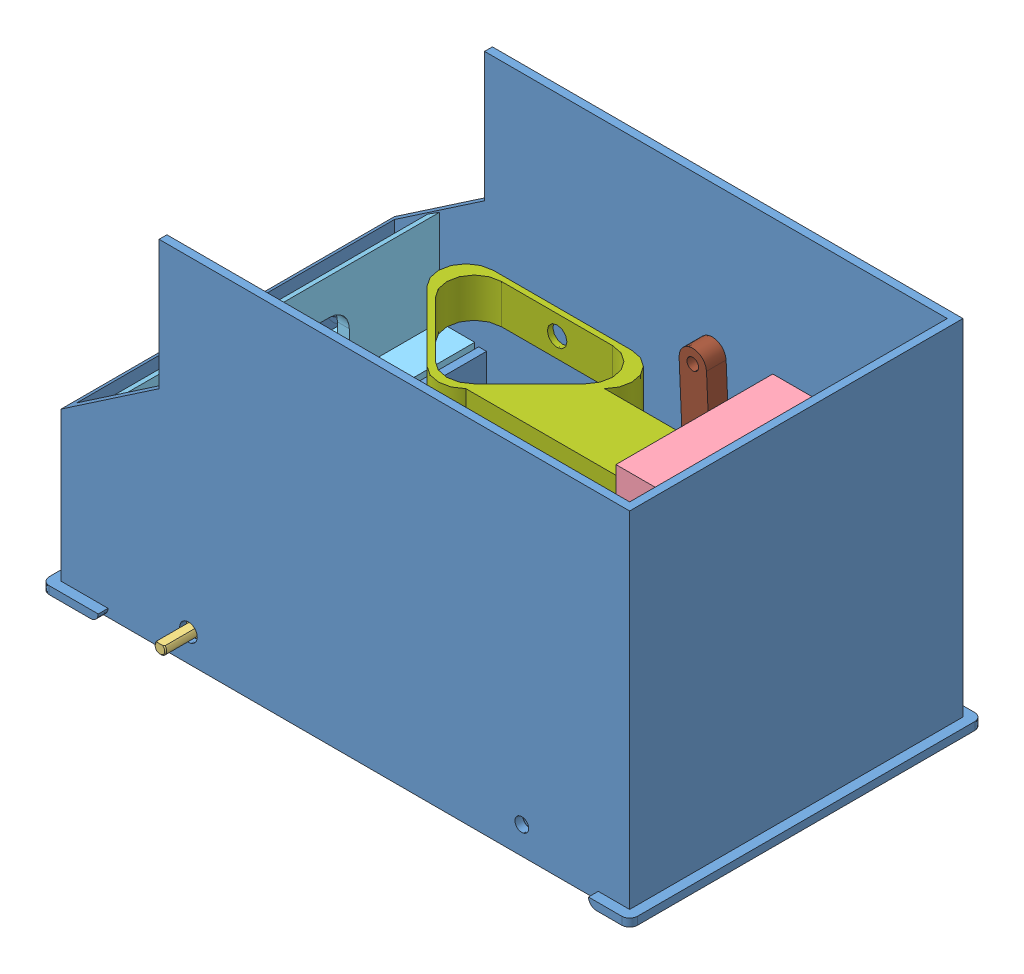
SolidWorks assembly Assemblage Robot, configuration Défaut. Lengths in mm.
Overall size (150 90 99.54).
20 component instances, 16 part files, 31 mates.
Components (placement in the parent):
- Assemblage_chassis-1: Assemblage_chassis [Défaut] at (-33.7926 -26.5183 11.2565) size (150 90 90)
  - chassis-1: chassis [Défaut] at (-70.5411 -39.149 105) size (150 90 90)
  - suppport arduino-1: suppport arduino [Défaut] at (13.9589 3.985 192.5) x (-1 0 0) z (0 -1 0) size (72 6 60)
- coque-1: coque [Défaut] at (-104.3337 -67.6673 194.8478) x (-1 0 0) z (0 0 -1) size (150 91.58 90) (hidden)
- Micro Moto Réducteur-2: Micro Moto Réducteur [Default] at (-69.3337 -60.6673 185.2565) size (12 10 35.27)
- Micro Moto Réducteur-3: Micro Moto Réducteur [Default] at (-69.3337 -60.6673 137.2565) x (-1 0 0) z (0 0 -1) size (12 10 35.27)
- Batterie-2: Batterie [Défaut] at (41.1663 10.3327 143.2565) x (0 1 0) z (0 0 1) size (76 22 40)
- Pièce1^Assemblage Robot-1: Pièce1^Assemblage Robot [Défaut] at origin (virtual)
- picèce led-1: picèce led [Défaut] at (-99.8337 -44.6673 201.2565) x (-1 0 0) z (0 0 -1) size (21 47.2 80)
- maintien-1: maintien [Défaut] at (5.3663 -65.6673 163.6265) x (-1 0 0) z (0 0 1) size (12 54.01 10)
- maintien-2: maintien [Défaut] at (5.3663 -65.6673 135.6565) x (-1 0 0) z (0 0 1) size (12 54.01 10)
- chassis terminer^Assemblage Robot-1: chassis terminer^Assemblage Robot [Défaut<Brut d'usinage>] at origin (virtual)
- support crayon-1: support crayon [Défaut] at (-43.6715 -21.6673 168.5763) x (-1 0 0) z (0 0 -1) size (83.19 10 31.68)
- goupille 6mm-1: goupille 6mm [Défaut] at (11.3663 -16.6673 153.6265) x (-0.72136 0.69256 0) z (0 0 1) size (6 6 40)
- servomoteur-1: servomoteur [Défaut] at (-1.4391 -65.6573 161.7565) x (0 1 0) z (-1 0 0) size (20 27 9)
- piece pignon servomoteur-1: piece pignon servomoteur [Default] at (-5.9391 -60.6573 135.7565) x (0.009859 0.999951 0) z (0 0 1) size (14.81 6 5)
- tige piece servomoteur-1: tige piece servomoteur [Default] at (-6.6703 -50.7455 130.7565) x (0.045193 -0.998978 0) z (0 0 1) size (52.61 7 5)
- Assem1-1: Assem1 [Default] at (9.8809 31.9191 223.8989) x (-1 0 0) z (0 -1 0) size (75.09 13.6 53.46)
  - Part1-1: Part1 [Default] at (-34.1666 27.7424 95.9952) size (75.09 13.6 53.46)
  - atmel-1: atmel [Default] at (44.5831 31.6424 63.6722) x (-1 0 0) z (0 0 -1) size (35.03 5.7 9)
Mates (geometry in assembly coordinates):
- Coïncidente64: coincident: line of Assemblage_chassis-1/chassis-1 through (-104.3337 -65.6673 204.2565) axis (0 0 -1); line of coque-1 through (-104.3337 -65.6673 106.8478) axis (0 0 1)
- Coïncidente65: coincident: plane of Assemblage_chassis-1/chassis-1 through (-104.3337 -65.6673 116.2565) normal (0 1 0); plane of Micro Moto Réducteur-2 through (-74.3337 -65.6673 200.7565) normal (0 -1 0)
- Coïncidente66: coincident: plane of Assemblage_chassis-1/chassis-1 through (41.1663 22.3327 120.7565) normal (0 0 1); plane of Micro Moto Réducteur-3 through (-64.3337 -64.6673 120.7565) normal (0 0 -1)
- Coïncidente67: coincident: plane of Assemblage_chassis-1/chassis-1 through (-104.3337 -65.6673 116.2565) normal (0 1 0); plane of Micro Moto Réducteur-3 through (-64.3337 -65.6673 121.7565) normal (0 -1 0)
- Distance25: distance = 29 mm: plane of Micro Moto Réducteur-3 through (-75.3337 -64.6673 121.7565) normal (-1 0 0); line of Assemblage_chassis-1/chassis-1 through (-104.3337 -65.6673 204.2565) axis (0 0 -1)
- Distance26: distance = 29 mm: plane of Micro Moto Réducteur-2 through (-75.3337 -64.6673 200.7565) normal (-1 0 0); line of Assemblage_chassis-1/chassis-1 through (-104.3337 -65.6673 204.2565) axis (0 0 -1)
- Coïncidente68: coincident: plane of Assemblage_chassis-1/chassis-1 through (-104.3337 -65.6673 116.2565) normal (0 1 0); plane of Batterie-2 through (19.1663 -65.6673 143.2565) normal (0 -1 0)
- Coïncidente69: coincident: plane of Assemblage_chassis-1/chassis-1 through (41.1663 22.3327 201.7565) normal (-1 0 0); plane of Batterie-2 through (41.1663 10.3327 143.2565) normal (1 0 0)
- Distance27: distance = 22.5 mm: plane of Batterie-2 through (19.1663 10.3327 143.2565) normal (0 0 -1); plane of Assemblage_chassis-1/chassis-1 through (41.1663 22.3327 120.7565) normal (0 0 1)
- Coïncidente70: coincident: plane of Assemblage_chassis-1/chassis-1 through (-104.3337 -65.6673 116.2565) normal (0 1 0); plane of picèce led-1 through (-99.8337 -65.6673 201.2565) normal (0 -1 0)
- Coïncidente71: coincident: plane of Assemblage_chassis-1/chassis-1 through (-99.8337 22.3327 120.7565) normal (1 0 0); plane of picèce led-1 through (-99.8337 -65.6673 201.2565) normal (-1 0 0)
- Distance28: distance = 0.5 mm: plane of Assemblage_chassis-1/chassis-1 through (-99.8337 22.3327 201.7565) normal (0 0 -1); plane of picèce led-1 through (-99.8337 -65.6673 201.2565) normal (0 0 1)
- Coïncidente72: coincident: plane of Assemblage_chassis-1/chassis-1 through (-104.3337 -65.6673 116.2565) normal (0 1 0); plane of maintien-1 through (17.3663 -65.6673 173.6265) normal (0 -1 0)
- Distance29: distance = 28.13 mm: plane of maintien-1 through (5.3663 -65.6673 173.6265) normal (0 0 1); plane of Assemblage_chassis-1/chassis-1 through (-99.8337 22.3327 201.7565) normal (0 0 -1)
- Coïncidente73: coincident: plane of Assemblage_chassis-1/chassis-1 through (-104.3337 -65.6673 116.2565) normal (0 1 0); plane of maintien-2 through (17.3663 -65.6673 145.6565) normal (0 -1 0)
- Distance30: distance = 14.9 mm: plane of maintien-2 through (5.3663 -65.6673 135.6565) normal (0 0 -1); plane of Assemblage_chassis-1/chassis-1 through (41.1663 22.3327 120.7565) normal (0 0 1)
- Distance31: distance = 23.8 mm: plane of maintien-1 through (17.3663 -11.6573 173.6265) normal (1 0 0); plane of Assemblage_chassis-1/chassis-1 through (41.1663 22.3327 201.7565) normal (-1 0 0)
- Distance32: distance = 23.8 mm: plane of maintien-2 through (17.3663 -11.6573 145.6565) normal (1 0 0); plane of Assemblage_chassis-1/chassis-1 through (41.1663 22.3327 201.7565) normal (-1 0 0)
- Coïncidente74: coincident: circle of maintien-1; circle of support crayon-1
- Coïncidente75: coincident: circle of maintien-2; cylinder of goupille 6mm-1 through (11.3663 -16.6673 173.6265) axis (0 0 -1) radius 3
- Coïncidente76: coincident: plane of Assemblage_chassis-1/chassis-1 through (-104.3337 -65.6573 116.2565) normal (0 1 0); plane of servomoteur-1 through (-10.4391 -65.6573 161.7565) normal (0 -1 0)
- Coïncidente77: coincident: plane of Assemblage_chassis-1/chassis-1 through (-99.8337 22.3327 201.7565) normal (0 0 -1); line of Micro Moto Réducteur-2 through (-64.3337 -55.6673 201.7565) axis (-1 0 0)
- Coïncidente78: coincident: plane of Assemblage_chassis-1/chassis-1 through (-0.8337 -65.6573 141.7565) normal (0 0 1); plane of servomoteur-1 through (-10.4391 -65.6573 141.7565) normal (0 0 -1)
- Coïncidente79: coincident: plane of Assemblage_chassis-1/chassis-1 through (-0.8337 -65.6573 141.7565) normal (0 0 1); plane of servomoteur-1 through (-10.4391 -65.6573 141.7565) normal (0 0 -1)
- Coïncidente82: coincident: plane of maintien-1 through (5.3663 -65.6673 173.6265) normal (0 0 1); circle of goupille 6mm-1
- Coaxiale2: concentric: cylinder of servomoteur-1 through (-5.9391 -60.6573 134.7565) axis (0 0 1) radius 1.8; cylinder of piece pignon servomoteur-1 through (-5.9391 -60.6573 140.7565) axis (0 0 -1) radius 1.5
- Coïncidente87: coincident: plane of servomoteur-1 through (-1.4391 -65.6573 140.7565) normal (0 0 -1); circle of piece pignon servomoteur-1
- Coïncidente88: coincident: circle of piece pignon servomoteur-1; circle of tige piece servomoteur-1
- Coaxiale3: concentric: circle of Assemblage_chassis-1/suppport arduino-1; circle of Assem1-1/Part1-1
- Coaxiale4: concentric: circle of Assemblage_chassis-1/suppport arduino-1; circle of Assem1-1/Part1-1
- Coïncidente90: coincident: plane of Assemblage_chassis-1/suppport arduino-1 through (-52.0145 -12.5468 197.7565) normal (0 0 -1); plane of Assem1-1/Part1-1 through (44.0475 -64.0761 197.7565) normal (0 0 1)
